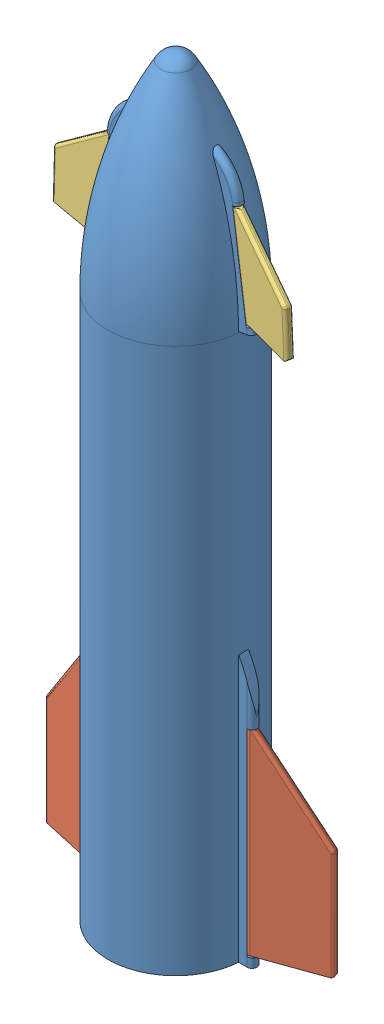
SolidWorks assembly StarshipModelAssem, configuration Default. Lengths in mm.
Overall size (93.51 250 45).
5 component instances, 3 part files, 10 mates.
Components (placement in the parent):
- StarshipModel-1: StarshipModel [Default] at origin size (58.4 250 45)
- StarshipTail-1: StarshipTail [Default] at (25.325 3.25 0) x (0.941308 0 -0.337548) z (0.337548 0 0.941308) size (23.22 65 2.45)
- StarshipTail-2: StarshipTail [Default] at (-25.325 3.25 0) x (-0.976196 0 -0.216889) z (0.216889 0 -0.976196) size (23.22 65 2.45)
- StarshipCanard-1: StarshipCanard [Default] at (-34.25 6.5386 2.7573) x (0.984342 0.002175 0.176255) z (-0.176255 0.024481 0.98404) size (23.93 32.04 2.45)
- StarshipCanard-2: StarshipCanard [Default] at (34.5117 6.575 -3.9483) x (-0.967615 0.004498 -0.252389) z (0.252389 0.035055 -0.966991) size (23.93 32.04 2.45)
Mates (geometry in assembly coordinates):
- Width1: width anti-aligned: plane of StarshipModel-1 through (0 68.5 0) normal (0 -1 0); plane of StarshipModel-1 through (0 3 0) normal (0 1 0); plane of StarshipTail-1 through (25.325 68.25 0) normal (0 1 0); plane of StarshipTail-1 through (25.325 3.25 0) normal (0 -1 0)
- Concentric1: concentric aligned: cylinder of StarshipTail-1 through (25.325 68.25 0) axis (0 -1 0) radius 0.56; cylinder of StarshipModel-1 through (25.325 71.5 0) axis (0 -1 0) radius 0.575
- Width2: width anti-aligned: plane of StarshipModel-1 through (0 68.5 0) normal (0 -1 0); plane of StarshipModel-1 through (0 3 0) normal (0 1 0); plane of StarshipTail-2 through (-25.325 68.25 0) normal (0 1 0); plane of StarshipTail-2 through (-25.325 3.25 0) normal (0 -1 0)
- Concentric2: concentric aligned: cylinder of StarshipTail-2 through (-25.325 68.25 0) axis (0 -1 0) radius 0.56; cylinder of StarshipModel-1 through (-25.325 71.5 0) axis (0 -1 0) radius 0.575
- Concentric3: concentric anti-aligned: cylinder of StarshipModel-1 through (20.4974 216.3869 0) axis (-0.137573 0.990492 0) radius 0.575; cylinder of StarshipCanard-2 through (19.9519 220.314 0) axis (0.137573 -0.990492 0) radius 0.56
- Concentric4: concentric anti-aligned: cylinder of StarshipCanard-1 through (-19.9519 220.314 0) axis (-0.137573 -0.990492 0) radius 0.56; cylinder of StarshipModel-1 through (-20.4974 216.3869 0) axis (0.137573 0.990492 0) radius 0.575
- Width3: width: plane of StarshipModel-1 through (29.0981 209.4984 0) normal (-0.137573 -0.990492 0); plane of StarshipCanard-1 through (24.5581 176.8122 0) normal (0.137573 0.990492 0); plane of StarshipModel-1 through (28.9605 208.5079 0) normal (0.137573 0.990492 0); plane of StarshipCanard-1 through (-25.0373 183.7007 0) normal (-0.137573 -0.990492 0)
- Width4: width: plane of StarshipModel-1 through (-24.5581 176.8122 0) normal (-0.137573 0.990492 0); plane of StarshipCanard-2 through (-29.0981 209.4984 0) normal (0.137573 -0.990492 0); plane of StarshipModel-1 through (-28.4276 208.5819 -7.3204) normal (-0.137573 0.990492 0); plane of StarshipCanard-2 through (25.0373 183.7007 0) normal (0.137573 -0.990492 0)
- Distance1: distance = 0.5 mm anti-aligned: plane of StarshipCanard-2 through (-19.5474 210.3201 -29.4452) normal (-0.137573 0.990492 0); plane of StarshipModel-1 through (-29.0981 209.4984 0) normal (0.137573 -0.990492 0)
- Distance2: distance = 0.5 mm anti-aligned: plane of StarshipCanard-1 through (21.7175 210.0187 26.1678) normal (0.137573 0.990492 0); plane of StarshipModel-1 through (29.0981 209.4984 0) normal (-0.137573 -0.990492 0)
